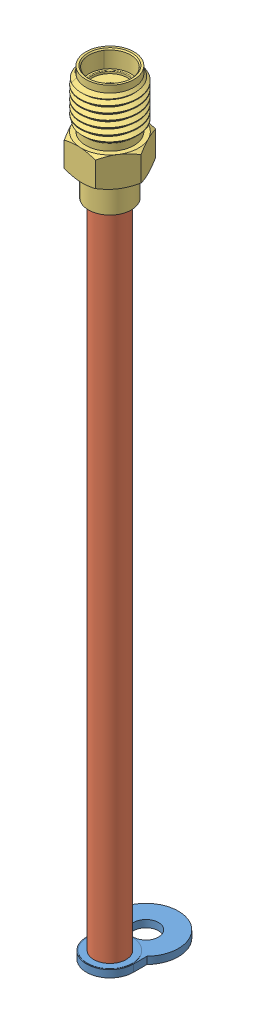
SolidWorks assembly 122001546, configuration Default. Lengths in mm.
Overall size (10.16 86.37 12.68).
3 component instances, 3 part files, 4 mates.
Components (placement in the parent):
- 121003119-1: 121003119 [Default] at origin size (7.2 0.85 10.2)
- 121003122-1: 121003122 [Default] at (0 0.8254 0) x (0.731519 0 0.681822) z (-0.681822 0 0.731519) size (3.58 77.47 3.58)
- 901-9704-1: 901-9704 [Default] at (0 73.2154 0) x (0 1 0) z (-0.546944 0 0.837169) size (12.71 7.34 7.34)
Mates (geometry in assembly coordinates):
- Concentric1: concentric anti-aligned: cylinder of 121003119-1 through (0 0 0) axis (0 1 0) radius 0.6; cylinder of 121003122-1 through (0 77.0254 0) axis (0 -1 0) radius 1.7907
- Coincident1: coincident anti-aligned: plane of 121003119-1 through (0 0.8254 0) normal (0 1 0); plane of 121003122-1 through (0 0.8254 0) normal (0 -1 0)
- Concentric2: concentric: cylinder of 121003122-1 through (0 77.0254 0) axis (0 -1 0) radius 1.7907; line of 901-9704-1 through (13.981 0 86.5559) axis (0 0 -1)
- Tangent2: tangent anti-aligned: plane of 121003122-1 through (0 77.0254 0) normal (0 1 0); face of 901-9704-1
